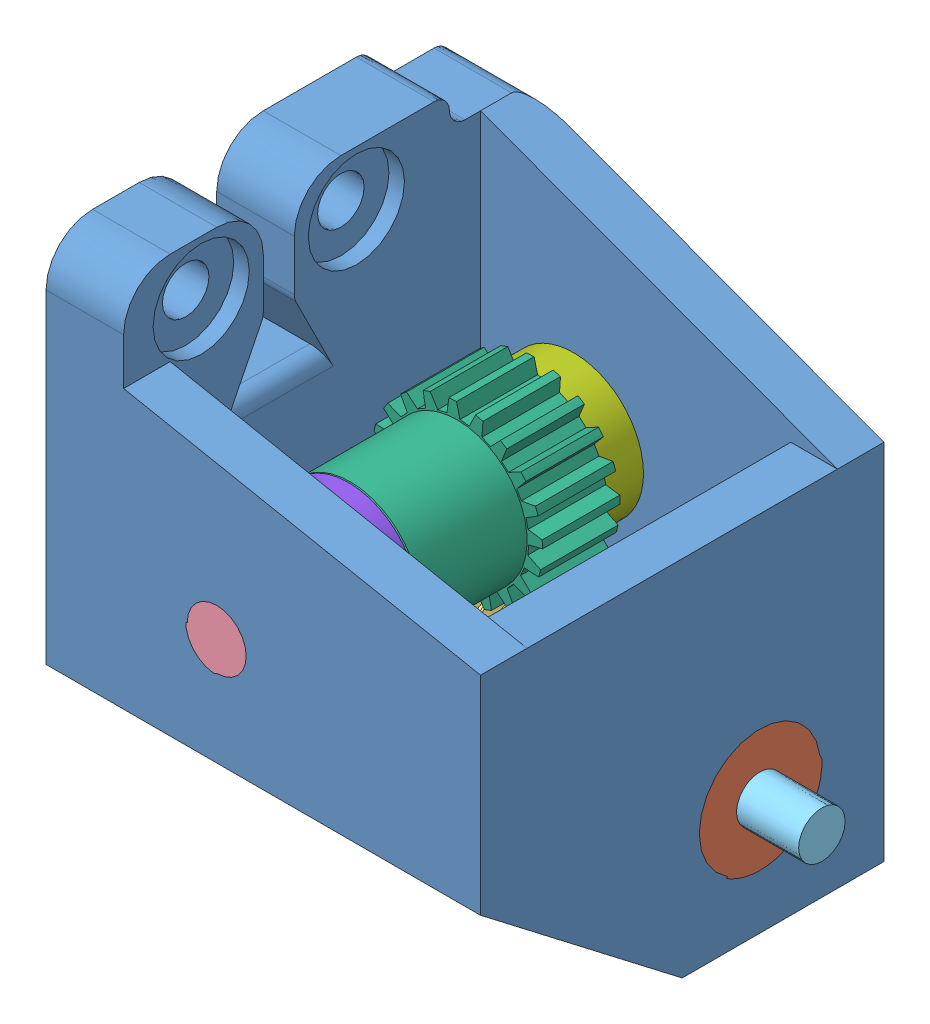
SolidWorks assembly 装配体4, configuration 默认. Lengths in mm.
Overall size (32 33.9 26).
9 component instances, 8 part files, 16 mates.
Components (placement in the parent):
- box - 0-1: box - 0 [默认] at (-1.5151 4.9306 23.8992) size (28 33.9 26)
- bearing-1: bearing [默认] at (-12.3151 -9.9694 28.8992) x (0 0 1) z (-1 0 0) size (9 9 3)
- bearing-2: bearing [默认] at (9.2849 -9.9694 28.8992) x (0 -0.428044 -0.903758) z (1 0 0) size (9 9 3)
- 零件2-1: 零件2 [默认] at (-11.5151 -9.9694 28.8992) x (1 0 0) z (0 -0.101118 0.994874) size (20 9.82 9.8)
- zhou1-1: zhou1 [默认] at (-5.5151 -0.5694 20.8992) x (1 0 0) z (0 -1 0) size (4 26 4)
- zhou2-1: zhou2 [默认] at (-14.5151 -9.9694 28.8992) x (0 0 -1) z (1 0 0) size (3 3 30)
- gear-1: gear [默认] at (-5.5151 -0.5694 31.3992) x (0 0 -1) z (0.913862 -0.406024 0) size (12 10.93 10.93)
- 1-1: 1 [默认] at (-5.5151 -0.5694 23.8992) x (0.998523 -0.054325 0) z (0 0 1) size (9 9 2.5)
- 2-1: 2 [默认] at (-5.5151 -0.5694 38.3992) x (0.999989 0.004731 0) z (0 0 1) size (9 9 5.5)
Mates (geometry in assembly coordinates):
- 同心1: concentric: cylinder of box - 0-1 through (-17.5151 -9.9694 28.8992) axis (1 0 0) radius 3.9; cylinder of bearing-1 through (-7.5151 -9.9694 28.8992) axis (-1 0 0) radius 1.5
- 重合2: coincident anti-aligned: plane of box - 0-1 through (-12.3151 -9.9694 28.8992) normal (1 0 0); plane of bearing-1 through (-12.3151 -9.9694 28.8992) normal (-1 0 0)
- 同心2: concentric anti-aligned: cylinder of box - 0-1 through (14.4849 -9.9694 28.8992) axis (-1 0 0) radius 3.9; cylinder of bearing-2 through (4.4849 -9.9694 28.8992) axis (1 0 0) radius 1.5
- 重合3: coincident anti-aligned: plane of box - 0-1 through (9.2849 -9.9694 28.8992) normal (-1 0 0); plane of bearing-2 through (9.2849 -9.9694 28.8992) normal (1 0 0)
- 同心3: concentric anti-aligned: cylinder of bearing-2 through (4.4849 -9.9694 28.8992) axis (1 0 0) radius 1.5; cylinder of zhou2-1 through (15.4849 -9.9694 28.8992) axis (-1 0 0) radius 1.5
- 重合4: coincident aligned: plane of bearing-1 through (-14.5151 -9.9694 28.8992) normal (-1 0 0); plane of zhou2-1 through (-14.5151 -9.9694 28.8992) normal (-1 0 0)
- 重合5: coincident aligned: circle of 零件2-1; cylinder of zhou2-1 through (15.4849 -9.9694 28.8992) axis (-1 0 0) radius 1.5
- 重合6: coincident anti-aligned: plane of bearing-1 through (-11.5151 -9.9694 28.8992) normal (1 0 0); plane of 零件2-1 through (-11.5151 -9.9694 28.8992) normal (-1 0 0)
- 同心4: concentric anti-aligned: cylinder of box - 0-1 through (-5.5151 -0.5694 20.0992) axis (0 0 1) radius 1.9; cylinder of zhou1-1 through (-5.5151 -0.5694 46.8992) axis (0 0 -1) radius 2
- 重合7: coincident aligned: plane of box - 0-1 through (-1.5151 4.9306 20.8992) normal (0 0 -1); plane of zhou1-1 through (-5.5151 -0.5694 20.8992) normal (0 0 -1)
- 同心5: concentric anti-aligned: cylinder of zhou1-1 through (-5.5151 -0.5694 46.8992) axis (0 0 -1) radius 2; cylinder of gear-1 through (-5.5151 -0.5694 18.3992) axis (0 0 1) radius 2
- 同心6: concentric aligned: cylinder of zhou1-1 through (-5.5151 -0.5694 46.8992) axis (0 0 -1) radius 2; cylinder of 1-1 through (-5.5151 -0.5694 26.3992) axis (0 0 -1) radius 2
- 同心7: concentric aligned: cylinder of zhou1-1 through (-5.5151 -0.5694 46.8992) axis (0 0 -1) radius 2; cylinder of 2-1 through (-5.5151 -0.5694 43.8992) axis (0 0 -1) radius 2
- 重合8: coincident anti-aligned: plane of box - 0-1 through (-1.5151 4.9306 23.8992) normal (0 0 1); plane of 1-1 through (-5.5151 -0.5694 23.8992) normal (0 0 -1)
- 重合9: coincident anti-aligned: plane of gear-1 through (-5.5151 -0.5694 26.3992) normal (0 0 -1); circle of 1-1
- 重合10: coincident anti-aligned: plane of gear-1 through (-5.5151 -0.5694 38.3992) normal (0 0 1); plane of 2-1 through (-5.5151 -0.5694 38.3992) normal (0 0 -1)
